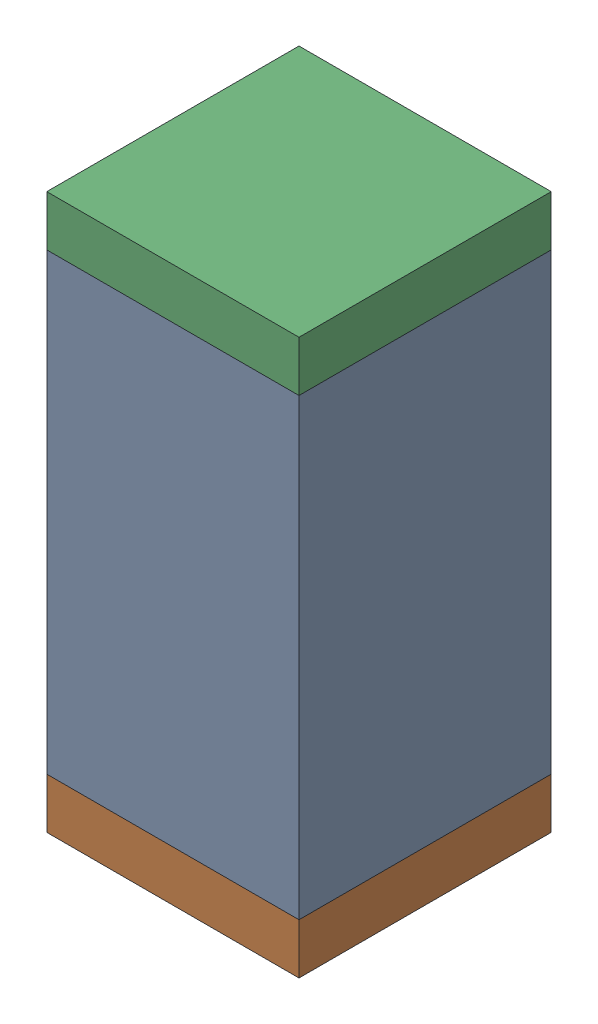
SolidWorks assembly C73, configuration Default. Lengths in mm.
Overall size (0.5 1.1 0.5).
6 component instances, 2 part files, 0 mates.
Components (placement in the parent):
- 791586336-1: 791586336 [Default] at (117.05 58.95 0) size (0.5 0.9 0.5)
  - Extruded_8-1: Extruded_8 [Default] at origin size (0.5 0.9 0.5)
- 810157360-1: 810157360 [Default] at (117.05 58.45 0) size (0.5 0.1 0.5)
  - Extruded_9-1: Extruded_9 [Default] at origin size (0.5 0.1 0.5)
- 810157360-2: 810157360 [Default] at (117.05 59.45 0) size (0.5 0.1 0.5)
  - Extruded_9-1: Extruded_9 [Default] at origin size (0.5 0.1 0.5)
